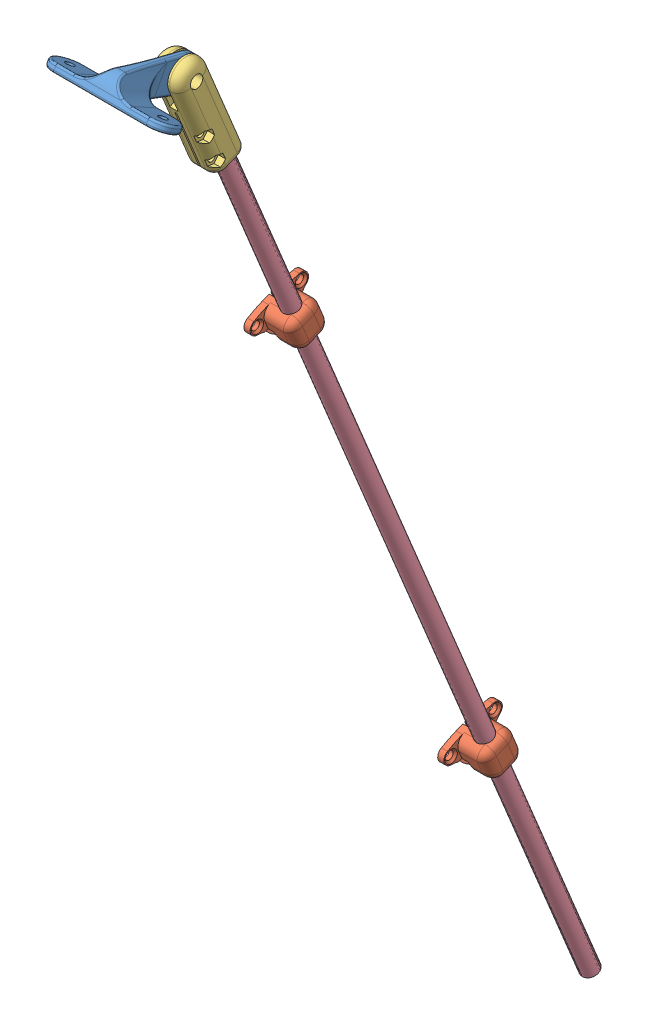
SolidWorks assembly Assem1, configuration Default. Lengths in mm.
Overall size (59.79 501.3 241.14).
5 component instances, 4 part files, 9 mates.
Components (placement in the parent):
- realsense mount-1: realsense mount [Default] at (49.0682 264.5527 139.0649) x (1 0 0) z (0 0.479545 0.877517) size (59.79 19.55 46.5)
- sidemount2-1: sidemount2 [Default] at (47.3182 -105.8943 -46.8969) x (0 0.381849 -0.924225) z (0 0.924225 0.381849) size (30 17 16)
- realsenseend-1: realsenseend [Default] at (48.8182 267.1721 109.4019) x (1 0 0) z (0 -0.924225 -0.381849) size (16 16 55)
- sidemount2-2: sidemount2 [Default] at (47.3182 120.8123 46.7684) x (0 0.381849 -0.924225) z (0 0.924225 0.381849) size (30 17 16)
- camera_rod-1: camera_rod [Default] at (48.8182 -214.5095 -91.7719) x (1 0 0) z (0 -0.381849 0.924225) size (8 500 8)
Mates (geometry in assembly coordinates):
- Concentric1: concentric aligned: cylinder of realsense mount-1 through (47.3182 259.7783 106.3471) axis (1 0 0) radius 3; cylinder of realsenseend-1 through (11.8182 259.7783 106.3471) axis (1 0 0) radius 3
- Coincident1: coincident anti-aligned: plane of realsense mount-1 through (50.8182 267.3842 136.9477) normal (1 0 0); plane of realsenseend-1 through (50.8182 254.8969 94.5924) normal (-1 0 0)
- Concentric2: concentric aligned: cylinder of camera_rod-1 through (48.8182 247.6028 99.1527) axis (0 -0.924225 -0.381849) radius 4; cylinder of realsenseend-1 through (48.8182 247.6028 99.1527) axis (0 -0.924225 -0.381849) radius 4
- Concentric3: concentric aligned: cylinder of camera_rod-1 through (48.8182 247.6028 99.1527) axis (0 -0.924225 -0.381849) radius 4; cylinder of sidemount2-1 through (48.8182 -91.1067 -40.7873) axis (0 -0.924225 -0.381849) radius 4
- Concentric4: concentric aligned: cylinder of camera_rod-1 through (48.8182 247.6028 99.1527) axis (0 -0.924225 -0.381849) radius 4; cylinder of sidemount2-2 through (48.8182 135.5999 52.878) axis (0 -0.924225 -0.381849) radius 4
- Coincident2: coincident anti-aligned: plane of realsenseend-1 through (48.8182 246.8391 101.0012) normal (0 -0.924225 -0.381849); plane of camera_rod-1 through (48.8182 247.6028 99.1527) normal (0 0.924225 0.381849)
- Parallel1: parallel anti-aligned: plane of assembly; plane of sidemount2-2 through (38.8182 135.5999 52.878) normal (-1 0 0)
- Parallel2: parallel anti-aligned: plane of assembly through (0 0 0) normal (1 0 0); plane of sidemount2-1 through (38.8182 -91.1067 -40.7873) normal (-1 0 0)
- Perpendicular1: perpendicular: plane of realsense mount-1 through (71.4651 264.5527 139.0649) normal (0 -0.877517 0.479545); plane of sidemount2-2 through (38.8182 135.5999 52.878) normal (-1 0 0)
